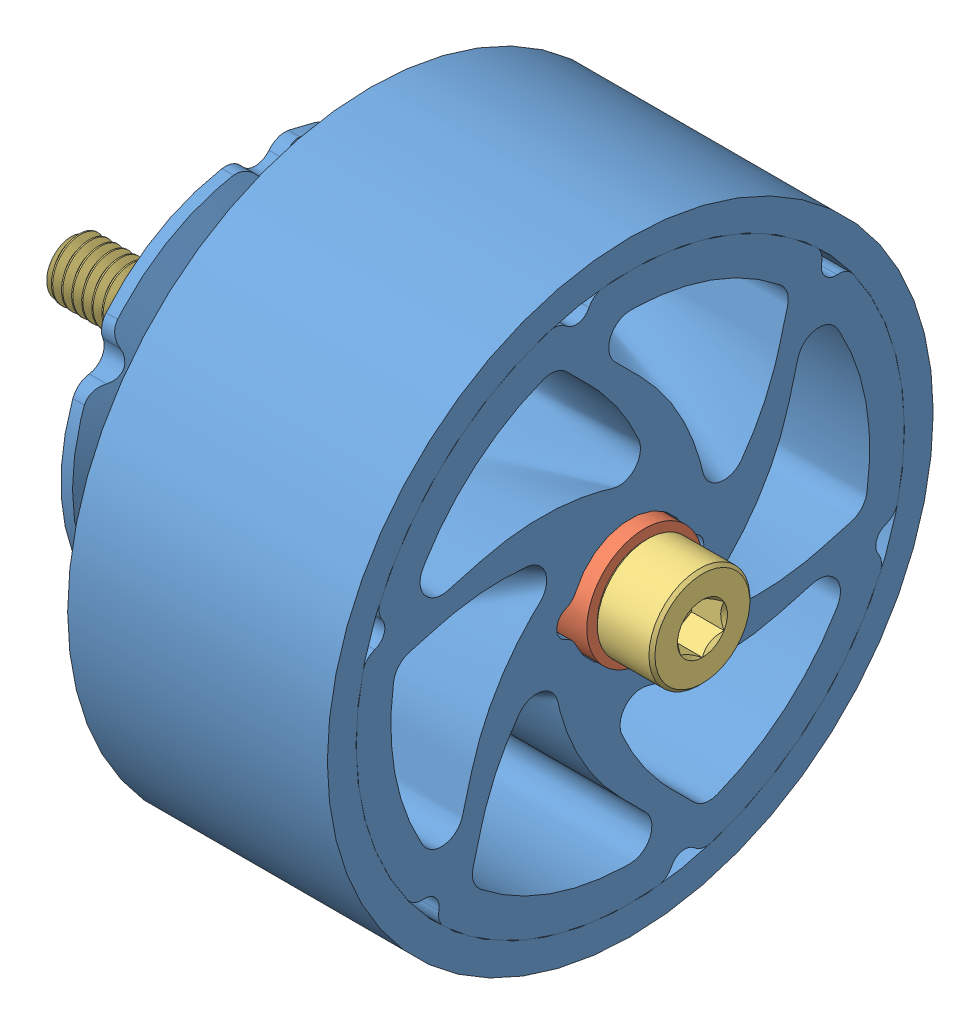
SolidWorks assembly wheel-asm, configuration front. Lengths in mm.
Overall size (44.38 42 42).
6 component instances, 5 part files, 11 mates.
Components (placement in the parent):
- wheel-1: wheel [Front] at origin size (26.01 42 42)
- wheel-bushing-4mm-8mm-8mm-1688K118-1: wheel-bushing-4mm-8mm-8mm-1688K118 [1688K118] at (8 0 0) x (0 0 -1) z (1 0 0) size (8.02 8.02 8)
- wheel-bushing-4mm-8mm-8mm-1688K118-2: wheel-bushing-4mm-8mm-8mm-1688K118 [1688K118] at (23 0 0) x (0 0 1) z (-1 0 0) size (8.02 8.02 8)
- screw-m4-40mm-partialthread-91502A133-1: screw-m4-40mm-partialthread-91502A133 [91502A133] at (-13 0 0) x (0 0 1) z (-1 0 0) size (7 7 44.38)
- nut-m4-nylock-94645A101-1: nut-m4-nylock-94645A101 [94645A101] at (1.5 0 0) x (0 -0.501948 0.864898) z (0 -0.864898 -0.501948) size (7 5 8.04)
- washer-m4-8mmod-98689A113-1: washer-m4-8mmod-98689A113 [98689A113] at (-1.25 0 0) x (0 -0.39847 0.917181) z (-1 0 0) size (8 8 0.5)
Mates (geometry in assembly coordinates):
- Coincident1: coordinate: point of wheel-1
- Concentric1: concentric anti-aligned: line of wheel-1 through (0 69.0457 0) axis (0 0 1); cylinder of wheel-bushing-4mm-8mm-8mm-1688K118-1 through (12 0 0) axis (-1 0 0) radius 4.01
- Concentric2: concentric anti-aligned: cylinder of wheel-bushing-4mm-8mm-8mm-1688K118-1 through (12 0 0) axis (-1 0 0) radius 4.01; cylinder of wheel-bushing-4mm-8mm-8mm-1688K118-2 through (19 0 0) axis (1 0 0) radius 4.01
- Coincident2: coincident: plane of assembly; point of wheel-1; plane of wheel-bushing-4mm-8mm-8mm-1688K118-1 through (12 0 0) normal (1 0 0)
- Coincident3: coincident: plane of assembly; point of wheel-1; plane of wheel-bushing-4mm-8mm-8mm-1688K118-2 through (19 0 0) normal (-1 0 0)
- Concentric3: concentric anti-aligned: line of wheel-1 through (0 69.0457 0) axis (0 0 1); cylinder of screw-m4-40mm-partialthread-91502A133-1 through (27 0 0) axis (-1 0 0) radius 2
- Coincident4: coincident anti-aligned: plane of wheel-bushing-4mm-8mm-8mm-1688K118-2 through (27 0 0) normal (1 0 0); plane of screw-m4-40mm-partialthread-91502A133-1 through (27 0 0) normal (-1 0 0)
- Coincident5: coincident aligned: line of wheel-1 through (0 69.0457 0) axis (0 0 1); line of nut-m4-nylock-94645A101-1 through (-1.25 0 0) axis (1 0 0)
- Coincident6: coincident anti-aligned: plane of wheel-bushing-4mm-8mm-8mm-1688K118-1 through (4 0 0) normal (-1 0 0); plane of nut-m4-nylock-94645A101-1 through (4 0 0) normal (1 0 0)
- Concentric4: concentric anti-aligned: line of wheel-1 through (0 69.0457 0) axis (0 0 1); cylinder of washer-m4-8mmod-98689A113-1 through (-1.5 0 0) axis (-1 0 0) radius 2.15
- Tangent1: tangent anti-aligned: torus of nut-m4-nylock-94645A101-1; plane of washer-m4-8mmod-98689A113-1 through (-1 1.9719 0.8567) normal (1 0 0)
